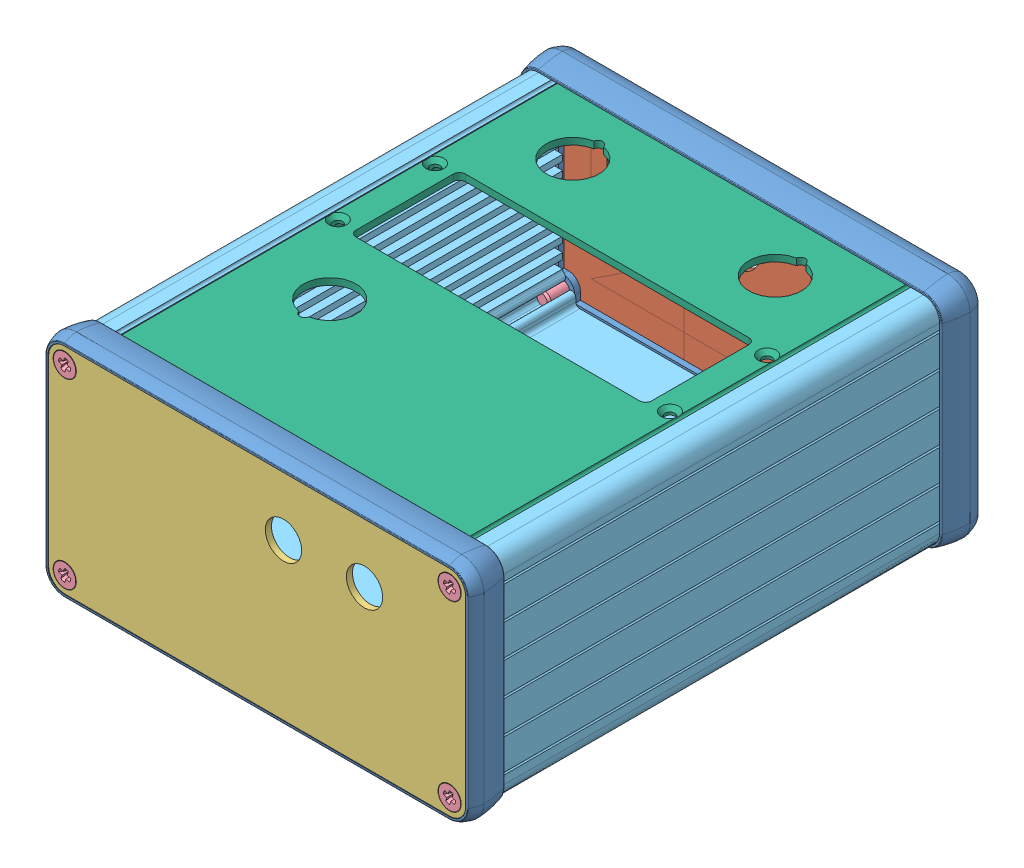
SolidWorks assembly Enclosure, configuration Défaut. Lengths in mm.
Overall size (106.15 56.13 126.01).
15 component instances, 6 part files, 24 mates.
Components (placement in the parent):
- Bezel Open-1: Bezel Open [Défaut] at (-29.0593 12.0561 -60) x (1 0 0) z (0 0 -1) size (106.13 56.13 9.01)
- Bezel Open-2: Bezel Open [Défaut] at (-29.0793 -12.5761 60) size (106.13 56.13 9.01)
- Back End Plate-5: Back End Plate [Défaut] at (0.01 -0.26 -62.15) x (1 0 0) z (0 0 -1) size (103 53 1.5)
- Front End Plate-4: Front End Plate [Défaut] at (-0.01 -0.26 62.15) size (103 53 1.5)
- 1455 screw-4-2: 1455 screw-4 [Défaut] at (-47.5 22.24 -62.9254) x (0.43184 0.90195 0) z (0 0 1) size (5.5 5.5 8)
- 1455 screw-4-4: 1455 screw-4 [Défaut] at (-47.52 -22.76 62.9254) x (-0.950123 0.311876 0) z (0 0 -1) size (5.5 5.5 8)
- Back End Plate-6: Back End Plate [Défaut] at (0.01 -0.26 -62.15) x (1 0 0) z (0 0 -1) size (103 53 1.5)
- 1455N Extrusion 120mm-4-1: 1455N Extrusion 120mm-4 [Défaut] x (1 0 0) z (0 0 -1) size (103 53 120)
- Cover-1: Cover [Défaut] at (0 26.08 0) x (-1 0 0) z (0 0 1) size (91.9 4.32 120)
- 1455 screw-4-9: 1455 screw-4 [Défaut] at (-47.5 -22.76 -62.9254) x (0.43184 0.90195 0) z (0 0 1) size (5.5 5.5 8)
- 1455 screw-4-10: 1455 screw-4 [Défaut] at (47.52 22.24 -62.9254) x (0.43184 0.90195 0) z (0 0 1) size (5.5 5.5 8)
- 1455 screw-4-11: 1455 screw-4 [Défaut] at (47.52 -22.76 -62.9254) x (0.43184 0.90195 0) z (0 0 1) size (5.5 5.5 8)
- 1455 screw-4-12: 1455 screw-4 [Défaut] at (-47.52 22.24 62.9254) x (-0.950123 0.311876 0) z (0 0 -1) size (5.5 5.5 8)
- 1455 screw-4-13: 1455 screw-4 [Défaut] at (47.5 -22.76 62.9254) x (-0.950123 0.311876 0) z (0 0 -1) size (5.5 5.5 8)
- 1455 screw-4-14: 1455 screw-4 [Défaut] at (47.5 22.24 62.9254) x (-0.950123 0.311876 0) z (0 0 -1) size (5.5 5.5 8)
Mates (geometry in assembly coordinates):
- Coïncidente4: coincident anti-aligned: plane of 1455N Extrusion 120mm-4-1 through (0 0 0) normal (0 0 -1); plane of assembly through (0 0 0) normal (0 0 1)
- Coïncidente5: coincident anti-aligned: plane of 1455N Extrusion 120mm-4-1 through (0 0 0) normal (0 -1 0); plane of assembly through (0 0 0) normal (0 1 0)
- Coïncidente6: coincident aligned: plane of 1455N Extrusion 120mm-4-1; plane of assembly through (0 0 0) normal (1 0 0)
- Coïncidente7: coincident anti-aligned: plane of Bezel Open-1 through (-50.805 -22.825 -60) normal (0 0 1); plane of 1455N Extrusion 120mm-4-1 through (0 -0.3141 -60) normal (0 0 -1)
- Coaxiale2: concentric aligned: cylinder of Bezel Open-1 through (-47.5 -22.76 -60) axis (0 0 -1) radius 1.75; cylinder of 1455N Extrusion 120mm-4-1 through (-47.5 -22.76 60) axis (0 0 -1) radius 4
- Coaxiale3: concentric aligned: cylinder of Bezel Open-1 through (-47.5 22.24 -60) axis (0 0 -1) radius 1.75; cylinder of 1455N Extrusion 120mm-4-1 through (-47.5 22.24 60) axis (0 0 -1) radius 4
- Coïncidente8: coincident anti-aligned: plane of Bezel Open-1 through (-50.805 -22.825 -61.4) normal (0 0 -1); plane of Back End Plate-6 through (0.01 -0.26 -61.4) normal (0 0 1)
- Coaxiale4: concentric aligned: cylinder of Bezel Open-1 through (47.52 22.24 -60) axis (0 0 -1) radius 1.75; cylinder of Back End Plate-6 through (47.52 22.24 -62.9) axis (0 0 -1) radius 1.75
- Coaxiale5: concentric aligned: cylinder of Bezel Open-1 through (-47.5 22.24 -60) axis (0 0 -1) radius 1.75; cylinder of Back End Plate-6 through (-47.5 22.24 -62.9) axis (0 0 -1) radius 1.75
- Coaxiale6: concentric anti-aligned: cylinder of Bezel Open-1 through (-47.5 22.24 -60) axis (0 0 -1) radius 1.75; cylinder of 1455 screw-4-2 through (-47.5 22.24 -61.775) axis (0 0 1) radius 1.75
- Coïncidente9: coincident aligned: circle of 1455 screw-4-2; circle of Back End Plate-6
- Coïncidente11: coincident anti-aligned: plane of Bezel Open-2 through (-50.825 22.305 60) normal (0 0 -1); plane of 1455N Extrusion 120mm-4-1 through (0 -0.3141 60) normal (0 0 1)
- Coaxiale9: concentric aligned: cylinder of Bezel Open-2 through (47.5 -22.76 60) axis (0 0 1) radius 1.75; cylinder of 1455N Extrusion 120mm-4-1 through (47.5 -22.76 -60) axis (0 0 1) radius 1.78
- Coaxiale12: concentric aligned: cylinder of Bezel Open-2 through (47.5 22.24 60) axis (0 0 1) radius 1.75; cylinder of 1455N Extrusion 120mm-4-1 through (47.5 22.24 -60) axis (0 0 1) radius 1.78
- Coïncidente12: coincident anti-aligned: plane of Bezel Open-2 through (-50.825 22.305 61.4) normal (0 0 1); plane of Front End Plate-4 through (-0.01 -0.26 61.4) normal (0 0 -1)
- Coaxiale13: concentric aligned: cylinder of Front End Plate-4 through (47.5 -22.76 62.9) axis (0 0 1) radius 1.75; cylinder of Bezel Open-2 through (47.5 -22.76 60) axis (0 0 1) radius 1.75
- Coaxiale14: concentric aligned: cylinder of Bezel Open-2 through (47.5 22.24 60) axis (0 0 1) radius 1.75; cylinder of Front End Plate-4 through (47.5 22.24 62.9) axis (0 0 1) radius 1.75
- Coïncidente15: coincident aligned: circle of Front End Plate-4; circle of 1455 screw-4-4
- Coïncidente22: coincident anti-aligned: plane of Bezel Open-1 through (-50.805 -22.825 -61.4) normal (0 0 -1); plane of Back End Plate-5 through (0.01 -0.26 -61.4) normal (0 0 1)
- Coaxiale15: concentric anti-aligned: cylinder of Back End Plate-5 through (-47.5 -22.76 -62.9) axis (0 0 -1) radius 1.75; cylinder of 1455 screw-4-9 through (-47.5 -22.76 -61.775) axis (0 0 1) radius 1.75
- Coaxiale16: concentric anti-aligned: cylinder of Back End Plate-5 through (-47.5 22.24 -62.9) axis (0 0 -1) radius 1.75; cylinder of 1455 screw-4-2 through (-47.5 22.24 -61.775) axis (0 0 1) radius 1.75
- Coïncidente23: coincident anti-aligned: plane of 1455N Extrusion 120mm-4-1 through (45.4747 21.86 -60) normal (0 1 0); plane of Cover-1 through (45.45 21.86 0) normal (0 -1 0)
- Coïncidente24: coincident anti-aligned: plane of 1455N Extrusion 120mm-4-1; plane of Cover-1
- Coïncidente25: coincident anti-aligned: plane of 1455N Extrusion 120mm-4-1 through (0 0 0) normal (0 0 -1); plane of Cover-1 through (0 26.08 0) normal (0 0 1)
